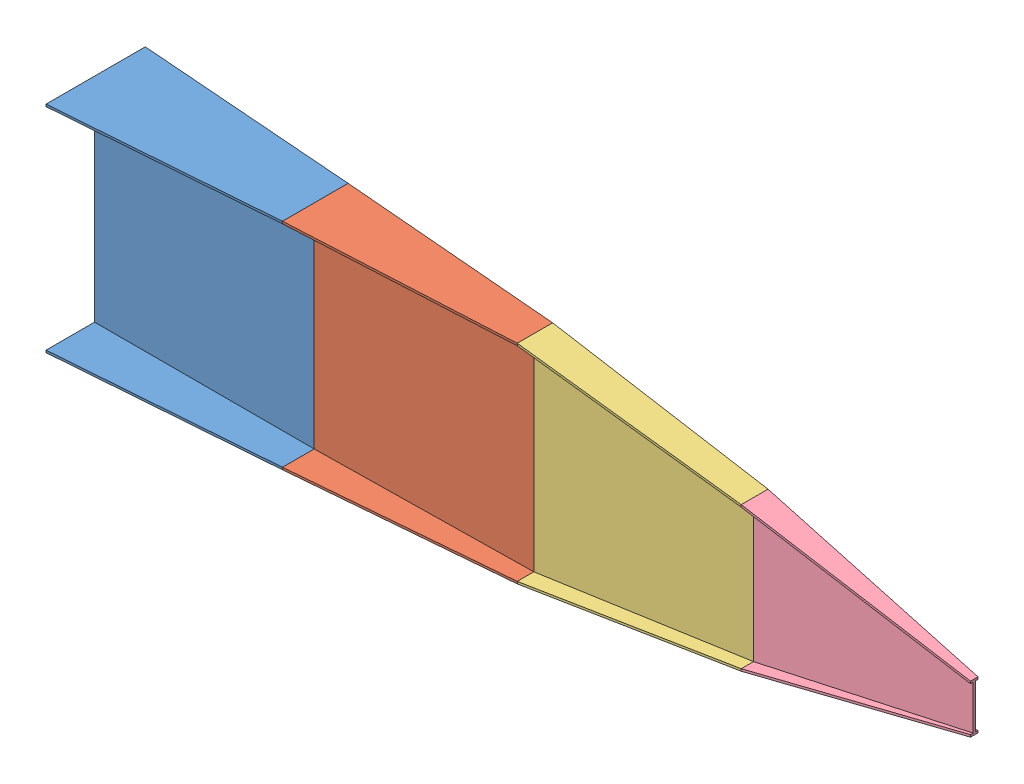
SolidWorks assembly 1.50 tolerance assembly, configuration Default. Lengths in mm.
Overall size (4000 980 452).
4 component instances, 4 part files, 9 mates.
Components (placement in the parent):
- 1-1: 1 [Default] at (-775.9263 612.0858 1043.8579) size (1000 980 452)
- 2-2: 2 [Default] at (224.0737 612.0858 1043.8579) size (1000 980 299)
- 3-2: 3 [Default] at (1224.0737 612.0858 1043.8579) size (1000 949 161)
- 4-2: 4 [Default] at (2224.0737 612.0858 1043.8579) size (1000 657 122)
Mates (geometry in assembly coordinates):
- Coincident39: coincident anti-aligned: plane of 1-1 through (224.0737 612.0858 1043.8579) normal (1 0 0); plane of 2-2 through (224.0737 612.0858 1043.8579) normal (-1 0 0)
- Coincident40: coincident anti-aligned: plane of 2-2 through (1224.0737 612.0858 1043.8579) normal (1 0 0); plane of 3-2 through (1224.0737 612.0858 1043.8579) normal (-1 0 0)
- Coincident42: coincident: point of 1-1; point of 2-2
- Coincident43: coincident: point of 1-1; point of 2-2
- Coincident44: coincident: point of 2-2; point of 3-2
- Coincident46: coincident: point of 2-2; point of 3-2
- Coincident49: coincident: point of 3-2; point of 4-2
- Coincident52: coincident aligned: plane of 3-2 through (1224.0737 612.0858 1053.8579) normal (0 0 1); plane of 4-2 through (2224.0737 612.0858 1053.8579) normal (0 0 1)
- Coincident53: coincident: point of 3-2; point of 4-2
